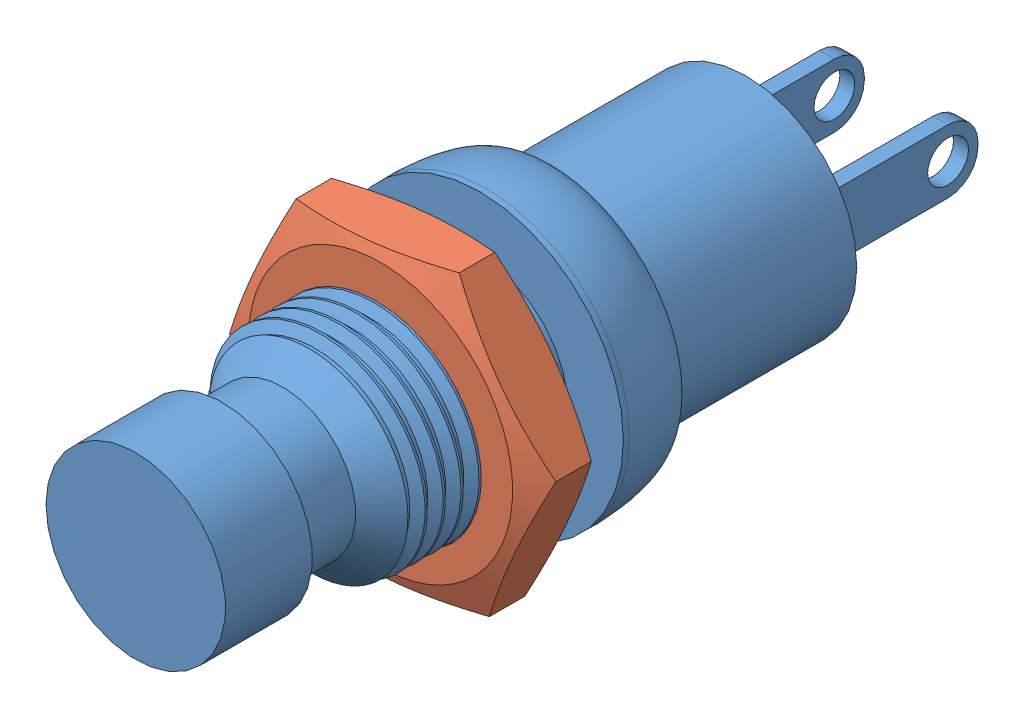
SolidWorks assembly Assem1, configuration Default. Lengths in mm.
Overall size (11.92 10.61 26).
2 component instances, 2 part files, 2 mates.
Components (placement in the parent):
- momentary pushbutton-1: momentary pushbutton [Default] at origin size (9.79 9.79 26)
- momentary button nut-1: momentary button nut [Default] at (0 0 10.2191) x (0.994337 0.106276 0) z (0 0 1) size (10.97 9.5 2.4)
Mates (geometry in assembly coordinates):
- Concentric1: concentric anti-aligned: circle of momentary pushbutton-1; circle of momentary button nut-1
- Coincident1: coordinate: point of momentary pushbutton-1
